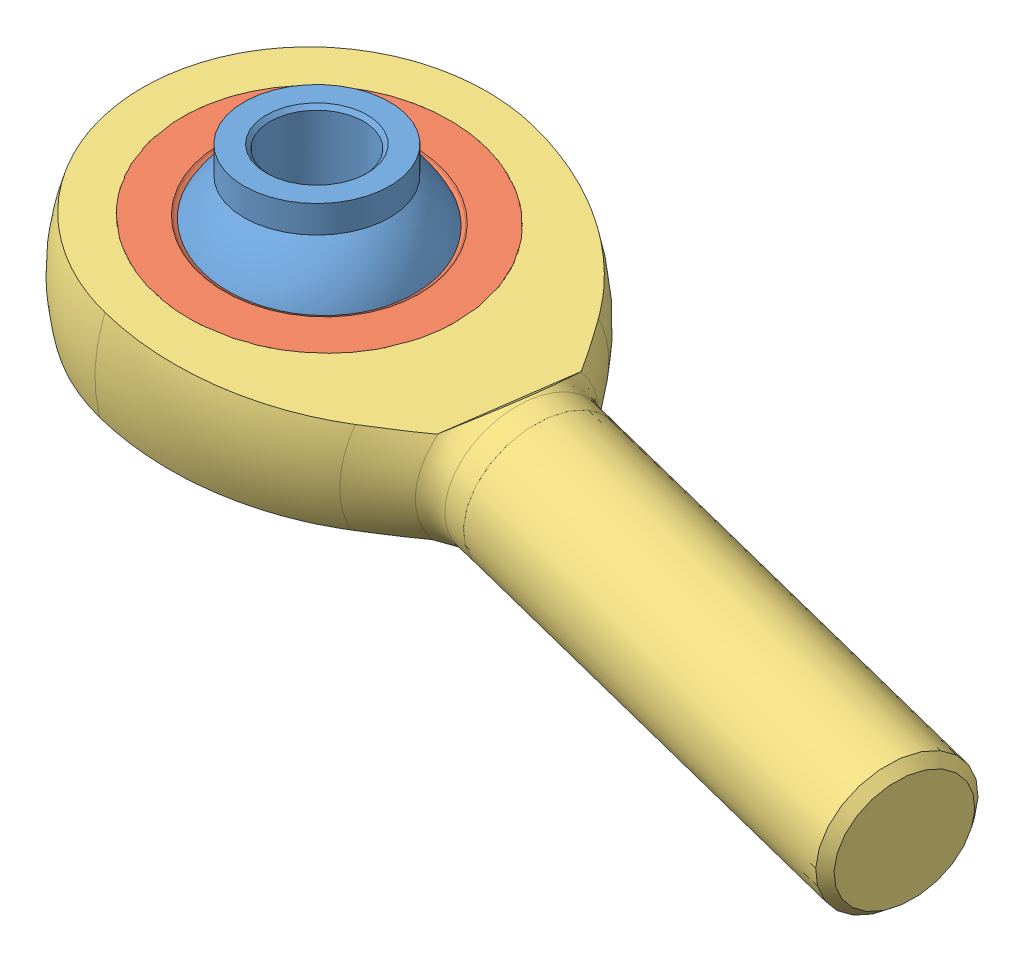
SolidWorks assembly HXAM-4T Rod End, configuration Default. Lengths in mm.
Overall size (68.56 33.24 38.87).
3 component instances, 3 part files, 4 mates.
Components (placement in the parent):
- HXAM-4T Ball-1: HXAM-4T Ball [Default] at (0 0 -49.2252) size (15.06 15.06 15.06)
- HXAM-4T Sleeve-1: HXAM-4T Sleeve [Default] at (48.2424 -5.1412 8.3283) x (-0.173187 -0.030424 0.984419) z (-0.980034 0.104443 -0.169188) size (19.53 6.73 19.53)
- HXAM-4T Housing-1: HXAM-4T Housing [Default] at (48.2424 -5.1412 8.3283) x (-0.173187 -0.030424 0.984419) z (-0.980034 0.104443 -0.169188) size (27.48 26.04 62.51)
Mates (geometry in assembly coordinates):
- Coincident2: coordinate: point of HXAM-4T Ball-1; point of assembly
- Coincident3: coincident: point of HXAM-4T Ball-1; point of HXAM-4T Sleeve-1
- Concentric1: concentric anti-aligned: cylinder of HXAM-4T Housing-1 through (0 0 0) axis (-0.097668 -0.994065 -0.047905) radius 9.3853; cylinder of HXAM-4T Sleeve-1 through (0 0 0) axis (0.097668 0.994065 0.047905) radius 9.3853
- Coincident4: coincident aligned: plane of HXAM-4T Housing-1; plane of HXAM-4T Sleeve-1
